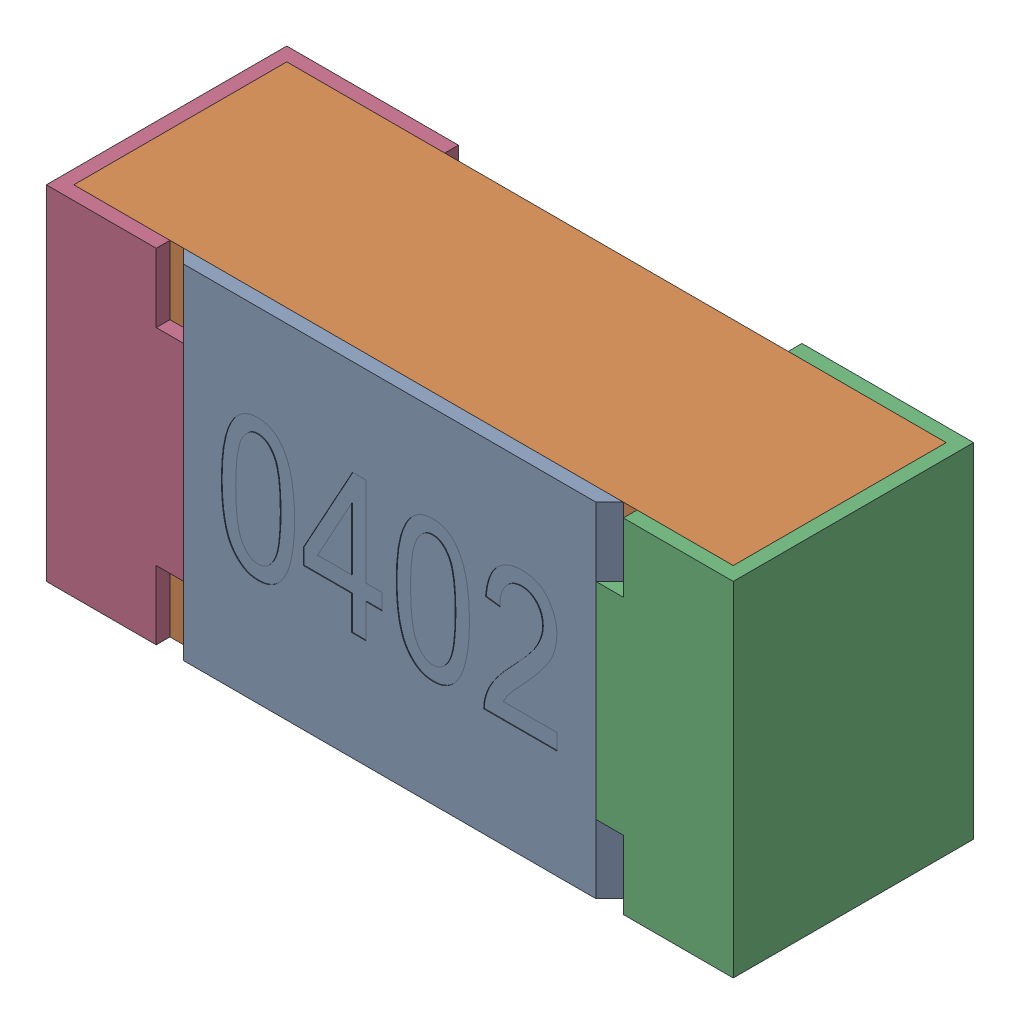
SolidWorks assembly R7, configuration Standard. Lengths in mm.
Overall size (1 0.5 0.35).
5 component instances, 4 part files, 0 mates.
Components (placement in the parent):
- R7-subassembly-1-1: R7-subassembly-1 [Standard] at (6.7001 -15.8 0) x (1 0 0) z (0 0 1) size (1 0.5 0.35)
  - User Library-R_0402-1: User Library-R_0402 [Standard] at origin size (0.64 0.5 0.02)
  - User Library-R_0402-1-1: User Library-R_0402-1 [Standard] at origin size (0.96 0.5 0.31)
  - User Library-R_0402-2-1: User Library-R_0402-2 [Standard] at origin size (0.25 0.5 0.35)
  - User Library-R_0402-3-1: User Library-R_0402-3 [Standard] at origin size (0.25 0.5 0.35)
